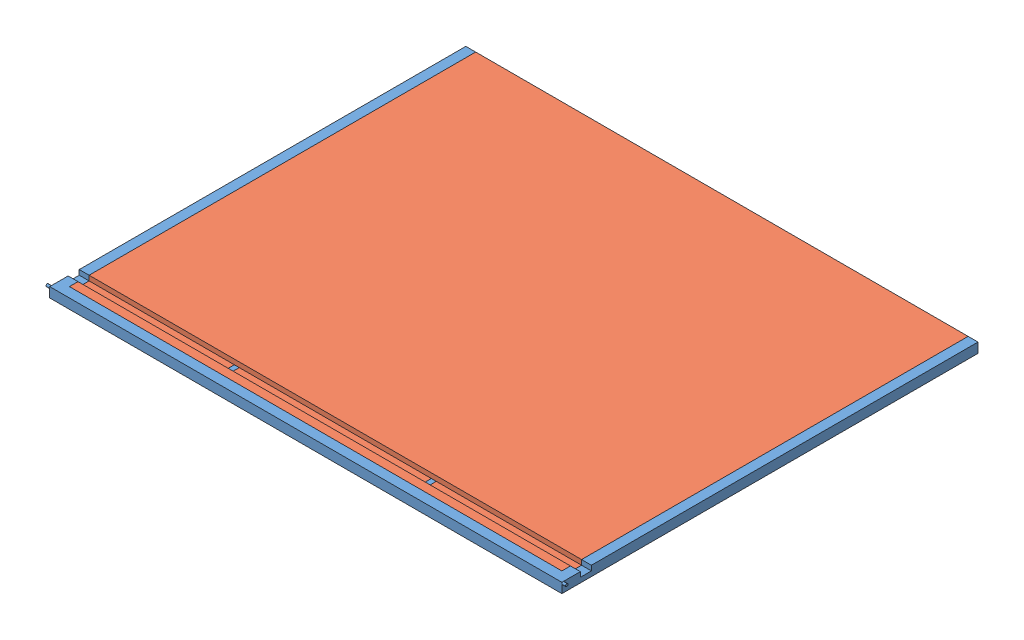
SolidWorks assembly FOLD CEILING_ASSEMBLY, configuration Default. Lengths in mm.
Overall size (2679.7 50.8 2146.3).
2 component instances, 2 part files, 11 mates.
Components (placement in the parent):
- CEILING MAIN FRAME-1: CEILING MAIN FRAME [Default] at (861.1039 1474.3497 2128.9979) size (2679.7 50.8 2146.3)
- CEILING_INSULATION-1: CEILING_INSULATION [Default] at (861.1039 1448.9497 2109.9479) x (0 0 -1) z (1 0 0) size (2095.5 50.8 2540)
Mates (geometry in assembly coordinates):
- Coincident2: coincident anti-aligned: plane of CEILING MAIN FRAME-1 through (-456.5211 1452.1247 1062.1979) normal (0 1 0); plane of ? through (-430.9941 1452.1247 1222.2179) normal (0 -1 0)
- Coincident3: coincident aligned: plane of CEILING MAIN FRAME-1 through (-459.6961 1499.7497 1062.1979) normal (-1 0 0); plane of ? through (-459.6961 1474.3497 650.7179) normal (-1 0 0)
- Coincident4: coincident anti-aligned: plane of CEILING MAIN FRAME-1 through (-461.0661 1499.7497 3157.6979) normal (0 0 -1); plane of CEILING_INSULATION-1 through (-408.8961 1499.7497 3157.6979) normal (0 0 1)
- Coincident5: coincident anti-aligned: plane of CEILING MAIN FRAME-1 through (2131.1039 1499.7497 3209.8679) normal (-1 0 0); plane of CEILING_INSULATION-1 through (2131.1039 1499.7497 3157.6979) normal (1 0 0)
- Coincident6: coincident aligned: plane of CEILING MAIN FRAME-1 through (-459.6961 1499.7497 1062.1979) normal (0 1 0); plane of CEILING_INSULATION-1 through (861.1039 1499.7497 2109.9479) normal (0 1 0)
- Coincident7: coincident aligned: plane of ? through (-453.3461 1448.9497 638.0179) normal (0 -1 0); plane of ? through (861.1039 1448.9497 866.6179) normal (0 -1 0)
- Coincident8: coincident anti-aligned: plane of ? through (-453.3461 1499.7497 663.4179) normal (0 0 1); plane of ? through (-408.8961 1480.6997 663.4179) normal (0 0 -1)
- Coincident9: coincident anti-aligned: plane of CEILING MAIN FRAME-1 through (2131.1039 1499.7497 3209.8679) normal (-1 0 0); plane of ? through (2131.1039 1480.6997 1069.8179) normal (1 0 0)
- Coincident10: coincident anti-aligned: plane of CEILING_INSULATION-1 through (-408.8961 1499.7497 1062.1979) normal (0 0 -1); plane of ? through (861.1039 1827.134 1062.1979) normal (0 0 1)
- Coincident12: coincident aligned: plane of CEILING MAIN FRAME-1 through (2181.9039 1499.7497 3209.8679) normal (1 0 0); plane of ? through (2181.9039 1846.184 1062.1979) normal (1 0 0)
- Coincident13: coincident anti-aligned: plane of ? through (-453.3461 1499.7497 663.4179) normal (0 0 1); plane of ? through (861.1039 1827.134 663.4179) normal (0 0 -1)
